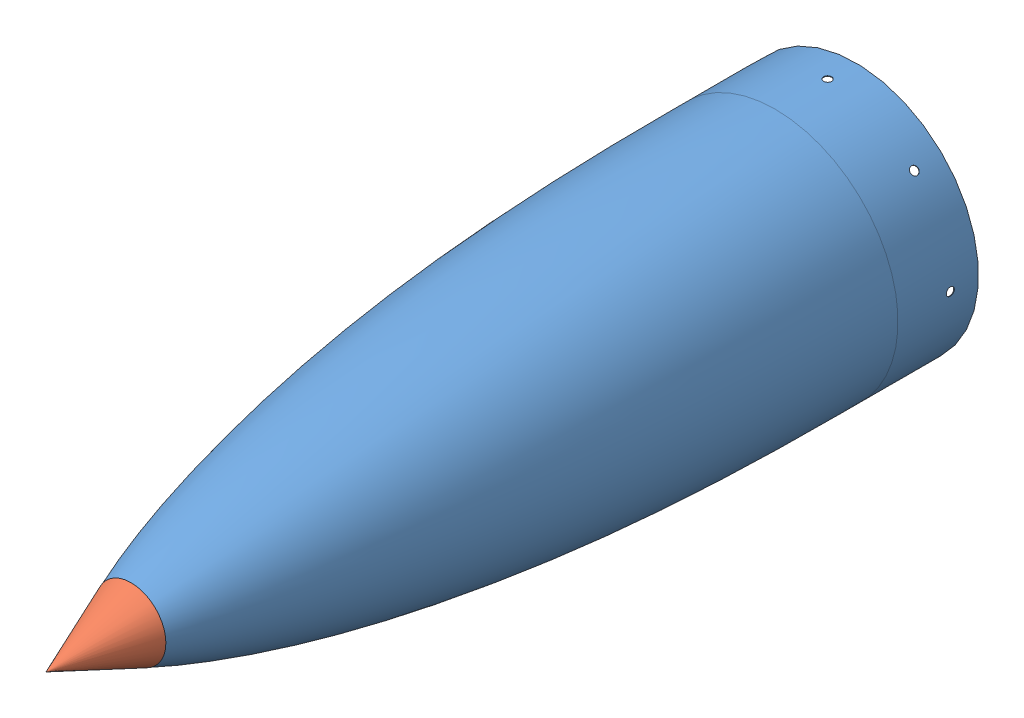
SolidWorks assembly A1_Nosecone, configuration Standard. Lengths in mm.
Overall size (123.76 123.76 402.33).
4 component instances, 4 part files, 10 mates.
Components (placement in the parent):
- Nosecone_Nosecone-1: Nosecone_Nosecone [Standard] x (0 0 -1) z (-1 0 0) size (360.09 123.76 123.76)
- Nosecone_Alutip-1: Nosecone_Alutip [Standard] x (0 0 -1) z (1 0 0) size (72.25 34.63 34.63)
- Nosecone_PLA_Insert-1: Nosecone_PLA_Insert [Standard] x (0 0 -1) z (1 0 0) size (20.14 48.68 48.68)
- Nosecone_M10_Nut-1: Nosecone_M10_Nut [Standard] at (0 0 -47.9885) x (0.866025 -0.5 0) z (0 0 1) size (19.48 17 7.7)
Mates (geometry in assembly coordinates):
- Deckungsgleich2: coincident: point of Nosecone_Nosecone-1
- Deckungsgleich3: coincident anti-aligned: plane of Nosecone_Nosecone-1 through (0 0 0) normal (-1 0 0)
- Deckungsgleich4: coincident anti-aligned: plane of Nosecone_Nosecone-1 through (0 0 0) normal (0 -1 0)
- Deckungsgleich6: coincident anti-aligned: circle of Nosecone_Nosecone-1; plane of Nosecone_Alutip-1 through (0 5 -30) normal (0 0 -1)
- Konzentrisch1: concentric anti-aligned: circle of Nosecone_Nosecone-1; circle of Nosecone_Alutip-1
- Konzentrisch2: concentric anti-aligned: circle of Nosecone_Alutip-1; circle of Nosecone_PLA_Insert-1
- Deckungsgleich8: coincident anti-aligned: plane of Nosecone_Alutip-1 through (0 5 -30) normal (0 0 -1); plane of Nosecone_PLA_Insert-1 through (0 0 -30) normal (0 0 1)
- Deckungsgleich9: coincident anti-aligned: plane of Nosecone_PLA_Insert-1 through (0 0 -44.1385) normal (0 0 -1); plane of Nosecone_M10_Nut-1 through (0 0 -44.1385) normal (0 0 1)
- Parallel1: parallel anti-aligned: line of Nosecone_PLA_Insert-1 through (0 9.815 -50.1385) axis (-0.866025 -0.5 0); line of Nosecone_M10_Nut-1 through (-8 4.6188 -51.8385) axis (0.866025 0.5 0)
- Konzentrisch3: concentric anti-aligned: circle of Nosecone_Alutip-1; circle of Nosecone_M10_Nut-1
